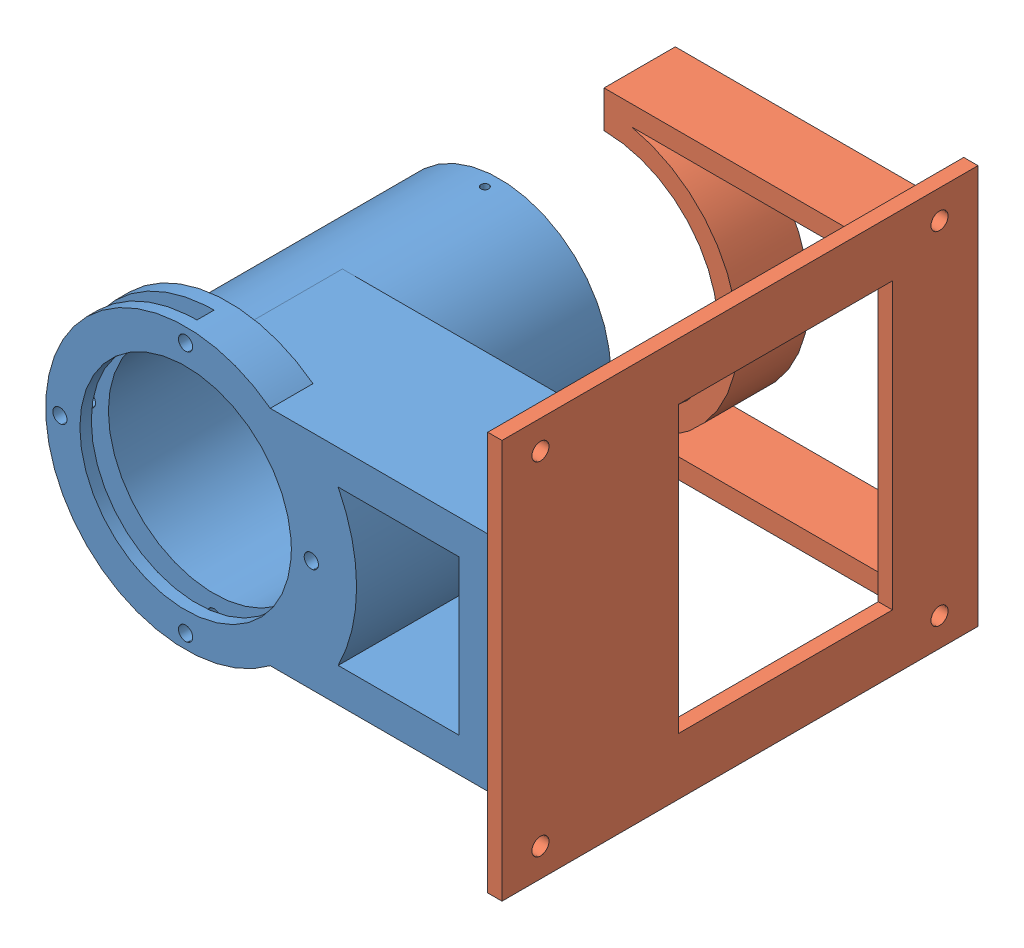
SolidWorks assembly pres+test, configuration Default. Lengths in mm.
Overall size (203.33 177.8 212.09).
2 component instances, 2 part files, 6 mates.
Components (placement in the parent):
- CompAdaptor_Redesigned-2: CompAdaptor_Redesigned [Default] x (1 0 0) z (0 0 -1) size (196.98 124.71 139.7)
- CompMount-1: CompMount [Default] at (6.096 0 -126.365) x (0 -1 0) z (0 0 -1) size (177.8 134.87 212.09)
Mates (geometry in assembly coordinates):
- Coincident4: coincident: plane of CompAdaptor_Redesigned-2 through (0 0 0) normal (0 0 -1); plane of assembly through (0 0 0) normal (0 0 1)
- Coincident5: coincident: plane of CompAdaptor_Redesigned-2 through (0 0 0) normal (0 -1 0); plane of assembly through (0 0 0) normal (0 1 0)
- Coincident6: coincident: plane of CompAdaptor_Redesigned-2 through (0 0 0) normal (1 0 0); plane of assembly through (0 0 0) normal (1 0 0)
- Coincident7: coincident: plane of CompAdaptor_Redesigned-2 through (134.62 47.117 69.85) normal (1 0 0); plane of CompMount-1 through (134.62 0 -142.24) normal (-1 0 0)
- Coincident8: coincident: plane of CompAdaptor_Redesigned-2 through (0 0 69.85) normal (0 0 1); plane of CompMount-1 through (134.62 269.3518 69.85) normal (0 0 1)
- Distance1: distance = 39.243 mm: plane of CompAdaptor_Redesigned-2 through (134.62 49.657 69.85) normal (0 1 0); plane of CompMount-1 through (6.096 88.9 -142.24) normal (0 1 0)
